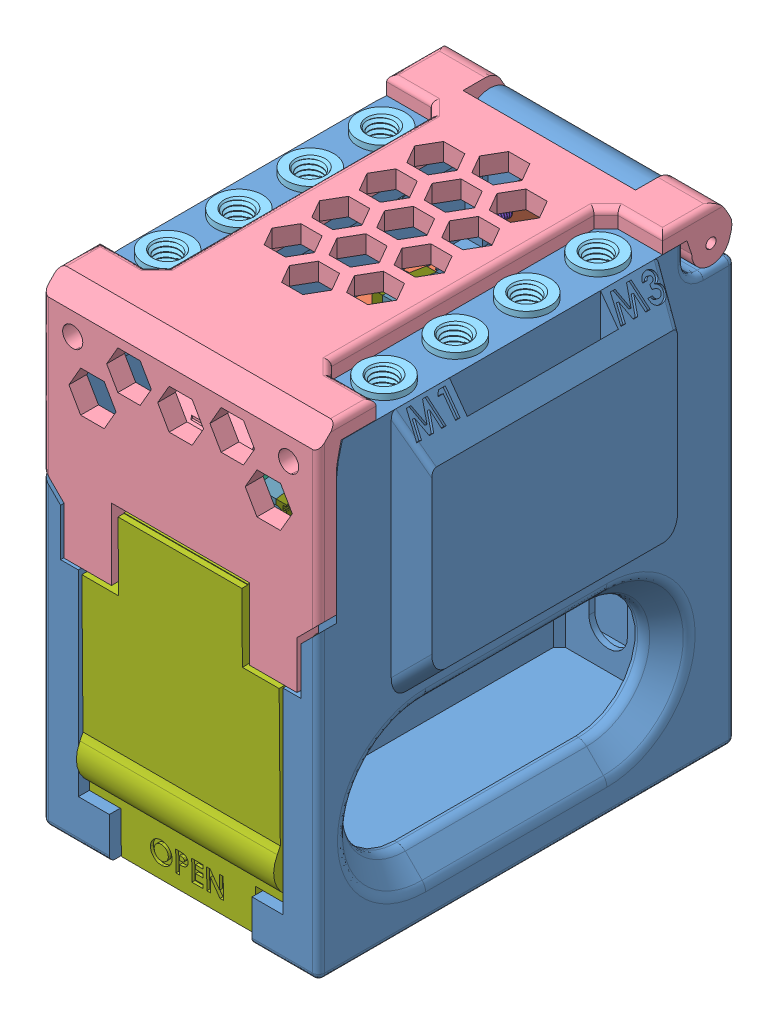
SolidWorks assembly Mechatron Assem, configuration Default. Lengths in mm.
Overall size (56.4 80.26 78.23).
218 component instances, 30 part files, 59 mates.
Components (placement in the parent):
- Mechatron base-1: Mechatron base [Default] at (42.9249 25.8036 66.6654)
- 250 Control Board V2 PCB.step-1: 250 Control Board V2 PCB.step [Default] at (27.2862 81.3679 113.6324) x (1 0 0) z (0 1 0) size (38.1 57.16 28.31)
  - Board.step-1: Board.step [Default] at origin size (38.1 57.15 1.61)
    - Open CASCADE STEP translator 6.8 1.1.1.step-1: Open CASCADE STEP translator 6.8 1.1.1.step [Default] at (0 0 -1.6143)
  - R2_MD4.step-1: R2_MD4.step [Default] at origin size (1.6 0.8 0.55)
    - ERJ-PB3B1002V,_10k_Resistor_(0603).step-1: ERJ-PB3B1002V,_10k_Resistor_(0603).step [Default] at (23.8148 22.4283 0) x (1 0 0) z (0 -1 0)
  - R2_MD3.step-1: R2_MD3.step [Default] at origin size (1.6 0.8 0.55)
    - ERJ-PB3B1002V,_10k_Resistor_(0603).step-1: ERJ-PB3B1002V,_10k_Resistor_(0603).step [Default] at (26.0349 24.1045 0) x (-1 0 0) z (0 1 0)
  - R2_MD2.step-1: R2_MD2.step [Default] at origin size (1.6 0.8 0.55)
    - ERJ-PB3B1002V,_10k_Resistor_(0603).step-1: ERJ-PB3B1002V,_10k_Resistor_(0603).step [Default] at (12.0651 22.4283 0) x (1 0 0) z (0 -1 0)
  - R2_MD1.step-1: R2_MD1.step [Default] at origin size (1.6 0.8 0.55)
    - ERJ-PB3B1002V,_10k_Resistor_(0603).step-1: ERJ-PB3B1002V,_10k_Resistor_(0603).step [Default] at (14.2747 24.1045 0) x (-1 0 0) z (0 1 0)
  - R1_MD4.step-1: R1_MD4.step [Default] at origin size (0.8 1.6 0.55)
    - AC0603FR-070RL,_0Ohm_Resistor_(0603).step-1: AC0603FR-070RL,_0Ohm_Resistor_(0603).step [Default] at (27.1168 10.7441 0) x (0 -1 0) z (-1 0 0)
  - R1_MD3.step-1: R1_MD3.step [Default] at origin size (0.8 1.6 0.55)
    - AC0603FR-070RL,_0Ohm_Resistor_(0603).step-1: AC0603FR-070RL,_0Ohm_Resistor_(0603).step [Default] at (22.7329 35.7887 0) x (0 1 0) z (1 0 0)
  - R1_MD2.step-1: R1_MD2.step [Default] at origin size (0.8 1.6 0.55)
    - AC0603FR-070RL,_0Ohm_Resistor_(0603).step-1: AC0603FR-070RL,_0Ohm_Resistor_(0603).step [Default] at (15.3671 10.7441 0) x (0 -1 0) z (-1 0 0)
  - R1_MD1.step-1: R1_MD1.step [Default] at origin size (0.8 1.6 0.55)
    - AC0603FR-070RL,_0Ohm_Resistor_(0603).step-1: AC0603FR-070RL,_0Ohm_Resistor_(0603).step [Default] at (10.9727 35.7887 0) x (0 1 0) z (1 0 0)
  - Q1.step-1: Q1.step [Default] at origin size (3.3 3.3 1.1)
    - CSD25404Q3T,_P-Channel_MOSFET.step-1: CSD25404Q3T,_P-Channel_MOSFET.step [Default] at (24.5109 53.3401 0) x (-1 0 0) z (0 1 0)
  - MCU1.step-1: MCU1.step [Default] at origin size (27.94 55.1 17.29)
    - ESP32-DEVKITC-32D,_ESP32_Development_Board.step-1: ESP32-DEVKITC-32D,_ESP32_Development_Board.step [Default] at (19.0499 25.3493 -1.6143) x (-1 0 0) z (0 0 -1) size (27.94 55.1 17.29)
      - header.step-1: header.step [Default] at (13.97 -21.59 0) x (1 0 0) z (0 -1 0) size (2.54 10.59 2.54)
        - header-0.step-1: header-0.step [Default] at origin
        - pin.step-1: pin.step [Default] at (-1.4 0 0)
      - header-1.step-1: header-1.step [Default] at (13.97 -19.05 0) x (1 0 0) z (0 -1 0) size (2.54 10.59 2.54)
        - header-0.step-1: header-0.step [Default] at origin
        - pin.step-1: pin.step [Default] at (-1.4 0 0)
      - header-2.step-1: header-2.step [Default] at (13.97 -16.51 0) x (1 0 0) z (0 -1 0) size (2.54 10.59 2.54)
        - header-0.step-1: header-0.step [Default] at origin
        - pin.step-1: pin.step [Default] at (-1.4 0 0)
      - header-3.step-1: header-3.step [Default] at (13.97 -13.97 0) x (1 0 0) z (0 -1 0) size (2.54 10.59 2.54)
        - header-0.step-1: header-0.step [Default] at origin
        - pin.step-1: pin.step [Default] at (-1.4 0 0)
      - header-4.step-1: header-4.step [Default] at (13.97 -11.43 0) x (1 0 0) z (0 -1 0) size (2.54 10.59 2.54)
        - header-0.step-1: header-0.step [Default] at origin
        - pin.step-1: pin.step [Default] at (-1.4 0 0)
      - header-5.step-1: header-5.step [Default] at (13.97 -8.89 0) x (1 0 0) z (0 -1 0) size (2.54 10.59 2.54)
        - header-0.step-1: header-0.step [Default] at origin
        - pin.step-1: pin.step [Default] at (-1.4 0 0)
      - header-6.step-1: header-6.step [Default] at (13.97 -6.35 0) x (1 0 0) z (0 -1 0) size (2.54 10.59 2.54)
        - header-0.step-1: header-0.step [Default] at origin
        - pin.step-1: pin.step [Default] at (-1.4 0 0)
      - header-7.step-1: header-7.step [Default] at (13.97 -3.81 0) x (1 0 0) z (0 -1 0) size (2.54 10.59 2.54)
        - header-0.step-1: header-0.step [Default] at origin
        - pin.step-1: pin.step [Default] at (-1.4 0 0)
      - header-8.step-1: header-8.step [Default] at (13.97 -1.27 0) x (1 0 0) z (0 -1 0) size (2.54 10.59 2.54)
        - header-0.step-1: header-0.step [Default] at origin
        - pin.step-1: pin.step [Default] at (-1.4 0 0)
      - header-9.step-1: header-9.step [Default] at (13.97 1.27 0) x (1 0 0) z (0 -1 0) size (2.54 10.59 2.54)
        - header-0.step-1: header-0.step [Default] at origin
        - pin.step-1: pin.step [Default] at (-1.4 0 0)
      - header-10.step-1: header-10.step [Default] at (13.97 3.81 0) x (1 0 0) z (0 -1 0) size (2.54 10.59 2.54)
        - header-0.step-1: header-0.step [Default] at origin
        - pin.step-1: pin.step [Default] at (-1.4 0 0)
      - header-11.step-1: header-11.step [Default] at (13.97 6.35 0) x (1 0 0) z (0 -1 0) size (2.54 10.59 2.54)
        - header-0.step-1: header-0.step [Default] at origin
        - pin.step-1: pin.step [Default] at (-1.4 0 0)
      - header-12.step-1: header-12.step [Default] at (13.97 8.89 0) x (1 0 0) z (0 -1 0) size (2.54 10.59 2.54)
        - header-0.step-1: header-0.step [Default] at origin
        - pin.step-1: pin.step [Default] at (-1.4 0 0)
      - header-13.step-1: header-13.step [Default] at (13.97 11.43 0) x (1 0 0) z (0 -1 0) size (2.54 10.59 2.54)
        - header-0.step-1: header-0.step [Default] at origin
        - pin.step-1: pin.step [Default] at (-1.4 0 0)
      - header-14.step-1: header-14.step [Default] at (13.97 13.97 0) x (1 0 0) z (0 -1 0) size (2.54 10.59 2.54)
        - header-0.step-1: header-0.step [Default] at origin
        - pin.step-1: pin.step [Default] at (-1.4 0 0)
      - header-15.step-1: header-15.step [Default] at (13.97 16.51 0) x (1 0 0) z (0 -1 0) size (2.54 10.59 2.54)
        - header-0.step-1: header-0.step [Default] at origin
        - pin.step-1: pin.step [Default] at (-1.4 0 0)
      - header-16.step-1: header-16.step [Default] at (13.97 19.05 0) x (1 0 0) z (0 -1 0) size (2.54 10.59 2.54)
        - header-0.step-1: header-0.step [Default] at origin
        - pin.step-1: pin.step [Default] at (-1.4 0 0)
      - header-17.step-1: header-17.step [Default] at (13.97 21.59 0) x (1 0 0) z (0 -1 0) size (2.54 10.59 2.54)
        - header-0.step-1: header-0.step [Default] at origin
        - pin.step-1: pin.step [Default] at (-1.4 0 0)
      - header-18.step-1: header-18.step [Default] at (13.97 24.13 0) x (1 0 0) z (0 -1 0) size (2.54 10.59 2.54)
        - header-0.step-1: header-0.step [Default] at origin
        - pin.step-1: pin.step [Default] at (-1.4 0 0)
      - header-19.step-1: header-19.step [Default] at (-11.43 -21.59 0) x (1 0 0) z (0 -1 0) size (2.54 10.59 2.54)
        - header-0.step-1: header-0.step [Default] at origin
        - pin.step-1: pin.step [Default] at (-1.4 0 0)
      - header-20.step-1: header-20.step [Default] at (-11.43 -19.05 0) x (1 0 0) z (0 -1 0) size (2.54 10.59 2.54)
        - header-0.step-1: header-0.step [Default] at origin
        - pin.step-1: pin.step [Default] at (-1.4 0 0)
      - header-21.step-1: header-21.step [Default] at (-11.43 -16.51 0) x (1 0 0) z (0 -1 0) size (2.54 10.59 2.54)
        - header-0.step-1: header-0.step [Default] at origin
        - pin.step-1: pin.step [Default] at (-1.4 0 0)
      - header-22.step-1: header-22.step [Default] at (-11.43 -13.97 0) x (1 0 0) z (0 -1 0) size (2.54 10.59 2.54)
        - header-0.step-1: header-0.step [Default] at origin
        - pin.step-1: pin.step [Default] at (-1.4 0 0)
      - header-23.step-1: header-23.step [Default] at (-11.43 -11.43 0) x (1 0 0) z (0 -1 0) size (2.54 10.59 2.54)
        - header-0.step-1: header-0.step [Default] at origin
        - pin.step-1: pin.step [Default] at (-1.4 0 0)
      - header-24.step-1: header-24.step [Default] at (-11.43 -8.89 0) x (1 0 0) z (0 -1 0) size (2.54 10.59 2.54)
        - header-0.step-1: header-0.step [Default] at origin
        - pin.step-1: pin.step [Default] at (-1.4 0 0)
      - header-25.step-1: header-25.step [Default] at (-11.43 -6.35 0) x (1 0 0) z (0 -1 0) size (2.54 10.59 2.54)
        - header-0.step-1: header-0.step [Default] at origin
        - pin.step-1: pin.step [Default] at (-1.4 0 0)
      - header-26.step-1: header-26.step [Default] at (-11.43 -3.81 0) x (1 0 0) z (0 -1 0) size (2.54 10.59 2.54)
        - header-0.step-1: header-0.step [Default] at origin
        - pin.step-1: pin.step [Default] at (-1.4 0 0)
      - header-27.step-1: header-27.step [Default] at (-11.43 -1.27 0) x (1 0 0) z (0 -1 0) size (2.54 10.59 2.54)
        - header-0.step-1: header-0.step [Default] at origin
        - pin.step-1: pin.step [Default] at (-1.4 0 0)
      - header-28.step-1: header-28.step [Default] at (-11.43 1.27 0) x (1 0 0) z (0 -1 0) size (2.54 10.59 2.54)
        - header-0.step-1: header-0.step [Default] at origin
        - pin.step-1: pin.step [Default] at (-1.4 0 0)
      - header-29.step-1: header-29.step [Default] at (-11.43 3.81 0) x (1 0 0) z (0 -1 0) size (2.54 10.59 2.54)
        - header-0.step-1: header-0.step [Default] at origin
        - pin.step-1: pin.step [Default] at (-1.4 0 0)
      - header-30.step-1: header-30.step [Default] at (-11.43 6.35 0) x (1 0 0) z (0 -1 0) size (2.54 10.59 2.54)
        - header-0.step-1: header-0.step [Default] at origin
        - pin.step-1: pin.step [Default] at (-1.4 0 0)
      - header-31.step-1: header-31.step [Default] at (-11.43 8.89 0) x (1 0 0) z (0 -1 0) size (2.54 10.59 2.54)
        - header-0.step-1: header-0.step [Default] at origin
        - pin.step-1: pin.step [Default] at (-1.4 0 0)
      - header-32.step-1: header-32.step [Default] at (-11.43 11.43 0) x (1 0 0) z (0 -1 0) size (2.54 10.59 2.54)
        - header-0.step-1: header-0.step [Default] at origin
        - pin.step-1: pin.step [Default] at (-1.4 0 0)
      - header-33.step-1: header-33.step [Default] at (-11.43 13.97 0) x (1 0 0) z (0 -1 0) size (2.54 10.59 2.54)
        - header-0.step-1: header-0.step [Default] at origin
        - pin.step-1: pin.step [Default] at (-1.4 0 0)
      - header-34.step-1: header-34.step [Default] at (-11.43 16.51 0) x (1 0 0) z (0 -1 0) size (2.54 10.59 2.54)
        - header-0.step-1: header-0.step [Default] at origin
        - pin.step-1: pin.step [Default] at (-1.4 0 0)
      - header-35.step-1: header-35.step [Default] at (-11.43 19.05 0) x (1 0 0) z (0 -1 0) size (2.54 10.59 2.54)
        - header-0.step-1: header-0.step [Default] at origin
        - pin.step-1: pin.step [Default] at (-1.4 0 0)
      - header-36.step-1: header-36.step [Default] at (-11.43 21.59 0) x (1 0 0) z (0 -1 0) size (2.54 10.59 2.54)
        - header-0.step-1: header-0.step [Default] at origin
        - pin.step-1: pin.step [Default] at (-1.4 0 0)
      - header-37.step-1: header-37.step [Default] at (-11.43 24.13 0) x (1 0 0) z (0 -1 0) size (2.54 10.59 2.54)
        - header-0.step-1: header-0.step [Default] at origin
        - pin.step-1: pin.step [Default] at (-1.4 0 0)
      - ESP32-DEVKITC-32D.STEP.step-1: ESP32-DEVKITC-32D.STEP.step [Default] at (0 0 11.94) x (1 0 0) z (0 -1 0)
  - M1_MD4.step-1: M1_MD4.step [Default] at origin size (4.9 6 1.7)
    - DRV8872DDARQ1,_H-Bridge.step-1: DRV8872DDARQ1,_H-Bridge.step [Default] at (26.4816 17.2991 0) x (0 -1 0) z (-1 0 0)
  - M1_MD3.step-1: M1_MD3.step [Default] at origin size (4.9 6 1.7)
    - DRV8872DDARQ1,_H-Bridge.step-1: DRV8872DDARQ1,_H-Bridge.step [Default] at (23.3681 29.2337 0) x (0 1 0) z (1 0 0)
  - M1_MD2.step-1: M1_MD2.step [Default] at origin size (4.9 6 1.7)
    - DRV8872DDARQ1,_H-Bridge.step-1: DRV8872DDARQ1,_H-Bridge.step [Default] at (14.7319 17.2991 0) x (0 -1 0) z (-1 0 0)
  - M1_MD1.step-1: M1_MD1.step [Default] at origin size (4.9 6 1.7)
    - DRV8872DDARQ1,_H-Bridge.step-1: DRV8872DDARQ1,_H-Bridge.step [Default] at (11.6079 29.2337 0) x (0 1 0) z (1 0 0)
  - LDO1.step-1: LDO1.step [Default] at origin size (7.29 6.72 1.81)
    - LD1117AS33TR,_3.3V_Linear_Regulator.step-1: LD1117AS33TR,_3.3V_Linear_Regulator.step [Default] at (6.3501 53.3399 0) x (0 -1 0) z (0 0 1)
  - J2.step-1: J2.step [Default] at origin size (10 7.5 15.1)
    - 691137710002,_2_Position_Terminal_Block_(16A).step-1: 691137710002,_2_Position_Terminal_Block_(16A).step [Default] at (38.06 57.0737 0) x (0 1 0) z (1 0 0) size (7.5 15.1 10)
      - MRT12P5_SX.step-1: MRT12P5_SX.step [Default] at origin
      - MRT12P5_CNT.step-1: MRT12P5_CNT.step [Default] at (0 0 -2.5)
      - MRT12P5_DX.step-1: MRT12P5_DX.step [Default] at (0 0 -7.5)
  - J1_MD4.step-1: J1_MD4.step [Default] at origin size (7.6 9.1 10.8)
    - 691214100002,_2_Position_Terminal_Block.step-1: 691214100002,_2_Position_Terminal_Block.step [Default] at (28.8186 9.0932 7.3152) x (1 0 0) z (0 -1 0) size (7.6 10.8 9.1)
      - 691214100002.step-1: 691214100002.step [Default] at origin
      - CPP3.5SQ_DX.step-1: CPP3.5SQ_DX.step [Default] at (-3.5 0 0)
      - CPP3.5SQ_SX.step-1: CPP3.5SQ_SX.step [Default] at (1.75 0 0)
  - J1_MD3.step-1: J1_MD3.step [Default] at origin size (7.6 9.1 10.8)
    - 691214100002,_2_Position_Terminal_Block.step-1: 691214100002,_2_Position_Terminal_Block.step [Default] at (21.0312 37.4396 7.3152) x (-1 0 0) z (0 1 0) size (7.6 10.8 9.1)
      - 691214100002.step-1: 691214100002.step [Default] at origin
      - CPP3.5SQ_DX.step-1: CPP3.5SQ_DX.step [Default] at (-3.5 0 0)
      - CPP3.5SQ_SX.step-1: CPP3.5SQ_SX.step [Default] at (1.75 0 0)
  - J1_MD2.step-1: J1_MD2.step [Default] at origin size (7.6 9.1 10.8)
    - 691214100002,_2_Position_Terminal_Block.step-1: 691214100002,_2_Position_Terminal_Block.step [Default] at (17.0688 9.0932 7.3152) x (1 0 0) z (0 -1 0) size (7.6 10.8 9.1)
      - 691214100002.step-1: 691214100002.step [Default] at origin
      - CPP3.5SQ_DX.step-1: CPP3.5SQ_DX.step [Default] at (-3.5 0 0)
      - CPP3.5SQ_SX.step-1: CPP3.5SQ_SX.step [Default] at (1.75 0 0)
  - J1_MD1.step-1: J1_MD1.step [Default] at origin size (7.6 9.1 10.8)
    - 691214100002,_2_Position_Terminal_Block.step-1: 691214100002,_2_Position_Terminal_Block.step [Default] at (9.271 37.4396 7.3152) x (-1 0 0) z (0 1 0) size (7.6 10.8 9.1)
      - 691214100002.step-1: 691214100002.step [Default] at origin
      - CPP3.5SQ_DX.step-1: CPP3.5SQ_DX.step [Default] at (-3.5 0 0)
      - CPP3.5SQ_SX.step-1: CPP3.5SQ_SX.step [Default] at (1.75 0 0)
  - D1.step-1: D1.step [Default] at origin size (5.36 2.91 2.69)
    - SMA6J12A-TR,_TVS_Diode,_13.3V_Breakdown.step-1: SMA6J12A-TR,_TVS_Diode,_13.3V_Breakdown.step [Default] at (16.7639 53.34 0) x (-1 0 0) z (0 0 1)
  - C5.step-1: C5.step [Default] at origin size (1.6 0.8 0.9)
    - CL10A106MA8NRNC,_10uF_Cap_(0603).step-1: CL10A106MA8NRNC,_10uF_Cap_(0603).step [Default] at (12.2429 53.34 0)
  - C4.step-1: C4.step [Default] at origin size (0.5 1 0.55)
    - CL05B104KB54PNC,_100nF_Cap_(0402).step-1: CL05B104KB54PNC,_100nF_Cap_(0402).step [Default] at (1.3461 53.2639 0) x (0 1 0) z (0 0 1)
  - C2_MD4.step-1: C2_MD4.step [Default] at origin size (1.25 2 1.35)
    - CL21A226MAQNNNE,_22uF_Cap_(0805).step-1: CL21A226MAQNNNE,_22uF_Cap_(0805).step [Default] at (20.0048 15.5091 0) x (0 -1 0) z (0 0 1)
  - C2_MD3.step-1: C2_MD3.step [Default] at origin size (1.25 2 1.35)
    - CL21A226MAQNNNE,_22uF_Cap_(0805).step-1: CL21A226MAQNNNE,_22uF_Cap_(0805).step [Default] at (29.718 31.0237 0) x (0 1 0) z (0 0 1)
  - C2_MD2.step-1: C2_MD2.step [Default] at origin size (1.25 2 1.35)
    - CL21A226MAQNNNE,_22uF_Cap_(0805).step-1: CL21A226MAQNNNE,_22uF_Cap_(0805).step [Default] at (8.255 15.5091 0) x (0 -1 0) z (0 0 1)
  - C2_MD1.step-1: C2_MD1.step [Default] at origin size (1.25 2 1.35)
    - CL21A226MAQNNNE,_22uF_Cap_(0805).step-1: CL21A226MAQNNNE,_22uF_Cap_(0805).step [Default] at (18.0848 31.0237 0) x (0 1 0) z (0 0 1)
  - C1_MD4.step-1: C1_MD4.step [Default] at origin size (1.25 2 1.35)
    - CL21A226MAQNNNE,_22uF_Cap_(0805).step-1: CL21A226MAQNNNE,_22uF_Cap_(0805).step [Default] at (22.5448 15.5091 0) x (0 -1 0) z (0 0 1)
  - C1_MD3.step-1: C1_MD3.step [Default] at origin size (1.25 2 1.35)
    - CL21A226MAQNNNE,_22uF_Cap_(0805).step-1: CL21A226MAQNNNE,_22uF_Cap_(0805).step [Default] at (27.305 31.0237 0) x (0 1 0) z (0 0 1)
  - C1_MD2.step-1: C1_MD2.step [Default] at origin size (1.25 2 1.35)
    - CL21A226MAQNNNE,_22uF_Cap_(0805).step-1: CL21A226MAQNNNE,_22uF_Cap_(0805).step [Default] at (10.795 15.5091 0) x (0 -1 0) z (0 0 1)
  - C1_MD1.step-1: C1_MD1.step [Default] at origin size (1.25 2 1.35)
    - CL21A226MAQNNNE,_22uF_Cap_(0805).step-1: CL21A226MAQNNNE,_22uF_Cap_(0805).step [Default] at (15.5448 31.0237 0) x (0 1 0) z (0 0 1)
- 98381A426_ALLOY STEEL DOWEL PIN-1: 98381A426_ALLOY STEEL DOWEL PIN [98381A426] at (46.3071 101.6184 53.9328)
- Mechatron Angled Door-1: Mechatron Angled Door [Default] at (45.6838 104.0269 77.7189) x (0 -0.000979 -1) z (1 0 0)
- 94510A250_Brass Screw-to-Expand Inserts-1: 94510A250_Brass Screw-to-Expand Inserts [94510A250] at (28.1371 104.9942 103.9328)
- 94510A250_Brass Screw-to-Expand Inserts-2: 94510A250_Brass Screw-to-Expand Inserts [94510A250] at (28.1371 104.9942 67.9328)
- 94510A250_Brass Screw-to-Expand Inserts-3: 94510A250_Brass Screw-to-Expand Inserts [94510A250] at (64.5371 104.9942 103.9328)
- 94510A250_Brass Screw-to-Expand Inserts-4: 94510A250_Brass Screw-to-Expand Inserts [94510A250] at (64.5371 104.9942 91.9328)
- 94510A250_Brass Screw-to-Expand Inserts-5: 94510A250_Brass Screw-to-Expand Inserts [94510A250] at (64.5371 104.9942 67.9328)
- 94510A250_Brass Screw-to-Expand Inserts-6: 94510A250_Brass Screw-to-Expand Inserts [94510A250] at (28.1371 104.9942 91.9328)
- 94510A250_Brass Screw-to-Expand Inserts-7: 94510A250_Brass Screw-to-Expand Inserts [94510A250] at (28.1371 104.9942 79.9328)
- 94510A250_Brass Screw-to-Expand Inserts-8: 94510A250_Brass Screw-to-Expand Inserts [94510A250] at (64.5371 104.9942 79.9328)
- 7395K650_ROCKER SWITCH-1: 7395K650_ROCKER SWITCH [7395K65] at (40.4105 73.7509 55.8256) x (0 -1 0) z (0 0 -1)
- 98381A426_ALLOY STEEL DOWEL PIN-2: 98381A426_ALLOY STEEL DOWEL PIN [98381A426] at (46.3851 73.4699 116.6842)
- Mechatron Side Door-1: Mechatron Side Door [Default] at (40.9971 47.9088 116.7432) x (0 -0.008497 0.999964) z (-1 0 0)
- 91292A832_18-8 Stainless Steel Socket Head Screw-1: 91292A832_18-8 Stainless Steel Socket Head Screw [91292A832] at (33.1257 87.2634 54.9328)
- 91292A832_18-8 Stainless Steel Socket Head Screw-2: 91292A832_18-8 Stainless Steel Socket Head Screw [91292A832] at (59.0157 87.2634 54.9328)
- 97258A101_18-8 Stainless Steel Thin Square Nut-1: 97258A101_18-8 Stainless Steel Thin Square Nut [97258A101] at (64.4938 100.2536 114.0328) x (1 0 0) z (0 1 0)
- 97258A101_18-8 Stainless Steel Thin Square Nut-2: 97258A101_18-8 Stainless Steel Thin Square Nut [97258A101] at (28.1805 100.2536 114.0328) x (1 0 0) z (0 1 0)
- 99461A928_Phillips Rounded Head Thread-Forming Screws-1: 99461A928_Phillips Rounded Head Thread-Forming Screws [99461A928] at (29.6103 81.3679 66.8583) x (0.837169 0 0.546944) z (0 1 0)
- 99461A928_Phillips Rounded Head Thread-Forming Screws-2: 99461A928_Phillips Rounded Head Thread-Forming Screws [99461A928] at (63.0621 81.3679 111.3083) x (0.837169 0 0.546944) z (0 1 0)
- voltage display-1: voltage display [Default] at (47.3245 87.0156 50.9328) x (1 0 0) z (0 1 0)
- 8262A16_FLUSH-MOUNT BALL NOSE SPRING PLUNGER-1: 8262A16_FLUSH-MOUNT BALL NOSE SPRING PLUNGER [8262A16] at (57.1997 39.9367 115.8241) x (0 0.978236 -0.207494) z (0 0.207494 0.978236)
- 8262A16_FLUSH-MOUNT BALL NOSE SPRING PLUNGER-2: 8262A16_FLUSH-MOUNT BALL NOSE SPRING PLUNGER [8262A16] at (35.3537 39.9367 115.8241) x (0 -1 0) z (0 0 1)
Mates (geometry in assembly coordinates):
- Parallel1: parallel anti-aligned: line of ME250 controller box final prototype v4-1 through (63.5371 87.0036 51.9328) axis (0 0 1); line of 250 Control Board V2 PCB.step-1/Board.step-1/Open CASCADE STEP translator 6.8 1.1.1.step-1 through (65.3862 79.7536 111.3084) axis (0 0 -1)
- Distance2: distance = 17.5 mm anti-aligned: plane of 250 Control Board V2 PCB.step-1/Board.step-1/Open CASCADE STEP translator 6.8 1.1.1.step-1 through (27.2862 79.7536 111.3084) normal (0 -1 0); plane of ME250 controller box final prototype v4-1 through (29.1371 62.2536 105.1328) normal (0 1 0)
- Coincident2: coincident anti-aligned: plane of Mechatron base-1 through (42.9249 104.0036 66.6654) normal (0 1 0); plane of top cover v8-1 through (45.6858 104.0036 77.7212) normal (0 -1 0)
- Coincident4: coincident aligned: plane of Mechatron base-1 through (23.1371 87.0036 49.9328) normal (-1 0 0); plane of top cover v8-1 through (23.1371 106.0036 118.9328) normal (-1 0 0)
- Coincident5: coincident aligned: plane of Mechatron base-1 through (23.1371 87.0036 49.9328) normal (0 0 -1); plane of top cover v8-1 through (23.1371 106.0036 49.9328) normal (0 0 -1)
- Concentric1: concentric anti-aligned: cylinder of ME250 controller box final prototype v4-1 through (69.5371 101.6184 53.9328) axis (-1 0 0) radius 0.8509; cylinder of 98381A426_ALLOY STEEL DOWEL PIN-1 through (27.2571 101.6184 53.9328) axis (1 0 0) radius 0.7937
- Distance3: distance = 5.08 mm aligned: plane of 98381A426_ALLOY STEEL DOWEL PIN-1 through (27.2571 101.6184 53.9328) normal (-1 0 0); plane of ME250 controller box final prototype v4-1 through (32.3371 25.8036 66.6654) normal (-1 0 0)
- Concentric3: concentric aligned: cylinder of 98381A426_ALLOY STEEL DOWEL PIN-1 through (27.2571 101.6184 53.9328) axis (1 0 0) radius 0.7937; cylinder of top cover v9-1 through (23.1351 101.6184 53.9328) axis (1 0 0) radius 0.8509
- Distance4: distance = 0.508 mm anti-aligned: plane of top cover v9-1 through (60.8451 101.6184 53.9328) normal (-1 0 0); plane of ME250 controller box final prototype v4-1 through (60.3371 25.8036 66.6654) normal (1 0 0)
- Coincident14: coincident anti-aligned: plane of ME250 controller box final prototype v4-1 through (42.9249 104.0036 66.6654) normal (0 1 0); plane of 94510A250_BRASS SCREW-TO-EXPAND INSERTS-1 through (28.1371 104.0036 103.9328) normal (0 -1 0)
- Concentric4: concentric anti-aligned: circle of ME250 controller box final prototype v4-1; circle of 94510A250_BRASS SCREW-TO-EXPAND INSERTS-1
- Coincident15: coincident anti-aligned: plane of ME250 controller box final prototype v4-1 through (42.9249 104.0036 66.6654) normal (0 1 0); plane of 94510A250_BRASS SCREW-TO-EXPAND INSERTS-8 through (64.5371 104.0036 79.9328) normal (0 -1 0)
- Coincident27: coincident aligned: plane of 94510A250_BRASS SCREW-TO-EXPAND INSERTS-4 through (64.5371 104.0036 91.9328) normal (0 -1 0); plane of 94510A250_BRASS SCREW-TO-EXPAND INSERTS-5 through (64.5371 104.0036 67.9328) normal (0 -1 0)
- Coincident28: coincident aligned: plane of 94510A250_BRASS SCREW-TO-EXPAND INSERTS-3 through (64.5371 104.0036 103.9328) normal (0 -1 0); plane of 94510A250_BRASS SCREW-TO-EXPAND INSERTS-5 through (64.5371 104.0036 67.9328) normal (0 -1 0)
- Coincident29: coincident anti-aligned: plane of ME250 controller box final prototype v4-1 through (42.9249 104.0036 66.6654) normal (0 1 0); plane of 94510A250_BRASS SCREW-TO-EXPAND INSERTS-5 through (64.5371 104.0036 67.9328) normal (0 -1 0)
- Coincident30: coincident anti-aligned: plane of ME250 controller box final prototype v4-1 through (42.9249 104.0036 66.6654) normal (0 1 0); plane of 94510A250_BRASS SCREW-TO-EXPAND INSERTS-4 through (64.5371 104.0036 91.9328) normal (0 -1 0)
- Coincident31: coincident anti-aligned: plane of ME250 controller box final prototype v4-1 through (42.9249 104.0036 66.6654) normal (0 1 0); plane of 94510A250_BRASS SCREW-TO-EXPAND INSERTS-5 through (64.5371 104.0036 67.9328) normal (0 -1 0)
- Coincident32: coincident anti-aligned: plane of ME250 controller box final prototype v4-1 through (42.9249 104.0036 66.6654) normal (0 1 0); plane of 94510A250_BRASS SCREW-TO-EXPAND INSERTS-3 through (64.5371 104.0036 103.9328) normal (0 -1 0)
- Coincident33: coincident anti-aligned: plane of ME250 controller box final prototype v4-1 through (42.9249 104.0036 66.6654) normal (0 1 0); plane of 94510A250_BRASS SCREW-TO-EXPAND INSERTS-2 through (28.1371 104.0036 67.9328) normal (0 -1 0)
- Coincident34: coincident anti-aligned: plane of ME250 controller box final prototype v4-1 through (42.9249 104.0036 66.6654) normal (0 1 0); plane of 94510A250_BRASS SCREW-TO-EXPAND INSERTS-5 through (64.5371 104.0036 67.9328) normal (0 -1 0)
- Coincident35: coincident anti-aligned: plane of ME250 controller box final prototype v4-1 through (42.9249 104.0036 66.6654) normal (0 1 0); plane of 94510A250_BRASS SCREW-TO-EXPAND INSERTS-6 through (28.1371 104.0036 91.9328) normal (0 -1 0)
- Coincident36: coincident anti-aligned: plane of ME250 controller box final prototype v4-1 through (42.9249 104.0036 66.6654) normal (0 1 0); plane of 94510A250_BRASS SCREW-TO-EXPAND INSERTS-7 through (28.1371 104.0036 79.9328) normal (0 -1 0)
- Concentric5: concentric anti-aligned: circle of ME250 controller box final prototype v4-1; circle of 94510A250_BRASS SCREW-TO-EXPAND INSERTS-6
- Concentric6: concentric anti-aligned: circle of ME250 controller box final prototype v4-1; circle of 94510A250_BRASS SCREW-TO-EXPAND INSERTS-7
- Concentric7: concentric anti-aligned: circle of ME250 controller box final prototype v4-1; circle of 94510A250_BRASS SCREW-TO-EXPAND INSERTS-2
- Concentric8: concentric aligned: circle of ME250 controller box final prototype v4-1; circle of 94510A250_BRASS SCREW-TO-EXPAND INSERTS-3
- Concentric9: concentric aligned: circle of ME250 controller box final prototype v4-1; circle of 94510A250_BRASS SCREW-TO-EXPAND INSERTS-4
- Concentric10: concentric aligned: circle of ME250 controller box final prototype v4-1; circle of 94510A250_BRASS SCREW-TO-EXPAND INSERTS-8
- Concentric11: concentric aligned: circle of ME250 controller box final prototype v4-1; circle of 94510A250_BRASS SCREW-TO-EXPAND INSERTS-5
- Coincident37: coincident anti-aligned: plane of ME250 controller box final prototype v4-1 through (23.1371 87.0036 49.9328) normal (0 0 -1); plane of 7395K650_ROCKER SWITCH-1 through (36.4355 69.8901 49.9328) normal (0 0 1)
- Parallel2: parallel anti-aligned: line of ME250 controller box final prototype v4-1 through (56.3701 77.0018 49.9328) axis (-1 0 0); line of 7395K650_ROCKER SWITCH-1 through (36.4355 78.2467 49.9328) axis (1 0 0)
- Distance5: distance = 0.0759 mm anti-aligned: plane of 7395K650_ROCKER SWITCH-1 through (37.2991 76.9259 63.9282) normal (0 1 0); plane of ME250 controller box final prototype v4-1 through (36.3041 77.0018 47.4328) normal (0 -1 0)
- Distance7: distance = 1.8245 mm anti-aligned: plane of ME250 controller box final prototype v4-1 through (56.3701 77.0018 47.4328) normal (-1 0 0); plane of 7395K650_ROCKER SWITCH-1 through (54.5457 78.8309 55.0128) normal (1 0 0)
- Concentric12: concentric anti-aligned: cylinder of top cover v9-1 through (69.5351 73.4699 116.6842) axis (-1 0 0) radius 0.8509; cylinder of 98381A426_ALLOY STEEL DOWEL PIN-2 through (27.3351 73.4699 116.6842) axis (1 0 0) radius 0.7937
- Distance8: distance = 0.5 mm aligned: plane of 98381A426_ALLOY STEEL DOWEL PIN-2 through (65.4351 73.4699 116.6842) normal (1 0 0); plane of top cover v9-1 through (65.9351 67.3369 77.7548) normal (1 0 0)
- Concentric13: concentric aligned: cylinder of 98381A426_ALLOY STEEL DOWEL PIN-2 through (27.3351 73.4699 116.6842) axis (1 0 0) radius 0.7937; cylinder of sidedoor v12-1 through (29.3847 73.4699 116.6842) axis (1 0 0) radius 1.1043
- Coincident39: coincident anti-aligned: plane of ME250 controller box final prototype v4-1 through (59.0157 87.2634 46.9328) normal (0 0 -1); plane of 91292A832_TYPE 18-8 SS SOCKET HEAD CAP SCREW-2 through (59.0157 87.2634 46.9328) normal (0 0 1)
- Coincident40: coincident anti-aligned: plane of ME250 controller box final prototype v4-1 through (33.1257 87.2634 46.9328) normal (0 0 -1); plane of 91292A832_TYPE 18-8 SS SOCKET HEAD CAP SCREW-1 through (33.1257 87.2634 46.9328) normal (0 0 1)
- Concentric16: concentric aligned: circle of ME250 controller box final prototype v4-1; circle of 91292A832_TYPE 18-8 SS SOCKET HEAD CAP SCREW-1
- Concentric19: concentric anti-aligned: circle of ME250 controller box final prototype v4-1; circle of 250 Control Board V2 PCB.step-1/Board.step-1/Open CASCADE STEP translator 6.8 1.1.1.step-1
- Coincident41: coincident anti-aligned: plane of ME250 controller box final prototype v4-1 through (67.3938 97.5036 114.9328) normal (0 0 -1); plane of 97258A101_18-8 Stainless Steel Thin Square Nut-1 through (61.7438 103.0036 114.9328) normal (0 0 1)
- Coincident42: coincident anti-aligned: plane of ME250 controller box final prototype v4-1 through (49.7494 97.5036 66.6654) normal (0 1 0); plane of 97258A101_18-8 Stainless Steel Thin Square Nut-1 through (61.7438 97.5036 113.1328) normal (0 -1 0)
- Coincident43: coincident anti-aligned: axis of ME250 controller box final prototype v4-1 through (64.4938 100.2536 114.9328) axis (0 0 1); line of 97258A101_18-8 Stainless Steel Thin Square Nut-1 through (64.4938 100.2536 115.7977) axis (0 0 -1)
- Coincident44: coincident anti-aligned: plane of ME250 controller box final prototype v4-1 through (25.2805 97.5036 114.9328) normal (0 0 -1); plane of 97258A101_18-8 Stainless Steel Thin Square Nut-2 through (25.4305 103.0036 114.9328) normal (0 0 1)
- Coincident45: coincident anti-aligned: plane of ME250 controller box final prototype v4-1 through (42.9249 97.5036 66.6654) normal (0 1 0); plane of 97258A101_18-8 Stainless Steel Thin Square Nut-2 through (25.4305 97.5036 113.1328) normal (0 -1 0)
- Coincident47: coincident aligned: line of ME250 controller box final prototype v4-1 through (28.1805 100.2536 114.9328) axis (0 0 1); line of 97258A101_18-8 Stainless Steel Thin Square Nut-2 through (28.1805 100.2536 113.1328) axis (0 0 1)
- Concentric20: concentric aligned: circle of ME250 controller box final prototype v4-1; circle of 99461A928_Phillips Rounded Head Thread-Forming Screws-2
- Coincident48: coincident anti-aligned: plane of 250 Control Board V2 PCB.step-1/Board.step-1/Open CASCADE STEP translator 6.8 1.1.1.step-1 through (27.2862 81.3679 111.3084) normal (0 1 0); plane of 99461A928_Phillips Rounded Head Thread-Forming Screws-2 through (63.445 81.3679 110.7223) normal (0 -1 0)
- Concentric21: concentric aligned: circle of 250 Control Board V2 PCB.step-1/Board.step-1/Open CASCADE STEP translator 6.8 1.1.1.step-1; circle of 99461A928_Phillips Rounded Head Thread-Forming Screws-1
- Coincident49: coincident anti-aligned: plane of 250 Control Board V2 PCB.step-1/Board.step-1/Open CASCADE STEP translator 6.8 1.1.1.step-1 through (27.2862 81.3679 111.3084) normal (0 1 0); plane of 99461A928_Phillips Rounded Head Thread-Forming Screws-1 through (29.9932 81.3679 66.2723) normal (0 -1 0)
- Concentric25: concentric aligned: circle of ME250 controller box final prototype v4-1; circle of 91292A832_TYPE 18-8 SS SOCKET HEAD CAP SCREW-2
- Coincident50: coincident anti-aligned: plane of ME250 controller box final prototype v4-1 through (42.9249 25.8036 50.9328) normal (0 0 1); plane of voltage display-1 through (47.3245 87.0156 50.9328) normal (0 0 -1)
- Distance9: distance = 0.6313 mm anti-aligned: plane of voltage display-1 through (34.8858 92.2821 44.9328) normal (0 1 0); plane of ME250 controller box final prototype v4-1 through (57.5207 92.9134 64.9328) normal (0 -1 0)
- Distance10: distance = 0.2651 mm anti-aligned: plane of voltage display-1 through (34.8858 82.2821 44.9328) normal (-1 0 0); plane of ME250 controller box final prototype v4-1 through (34.6207 92.9134 64.9328) normal (1 0 0)
- Distance11: distance = 1.13 mm anti-aligned: plane of sidedoor v12-1 through (35.8651 80.4523 117.0197) normal (-1 0 0); plane of top cover v9-1 through (34.7351 73.4282 120.9931) normal (1 0 0)
- Concentric28: concentric anti-aligned: circle of sidedoor v12-1; circle of 8262A16_FLUSH-MOUNT BALL NOSE SPRING PLUNGER-2
- Coincident54: coincident anti-aligned: plane of sidedoor v12-1 through (42.8467 39.9367 115.8241) normal (-1 0 0); plane of 8262A16_FLUSH-MOUNT BALL NOSE SPRING PLUNGER-2 through (42.8467 39.9367 118.6626) normal (1 0 0)
- Concentric29: concentric aligned: circle of sidedoor v12-1; circle of 8262A16_FLUSH-MOUNT BALL NOSE SPRING PLUNGER-1
- Coincident55: coincident anti-aligned: plane of sidedoor v12-1 through (49.7067 39.9367 115.8241) normal (1 0 0); plane of 8262A16_FLUSH-MOUNT BALL NOSE SPRING PLUNGER-1 through (49.7067 40.5256 118.6008) normal (-1 0 0)
